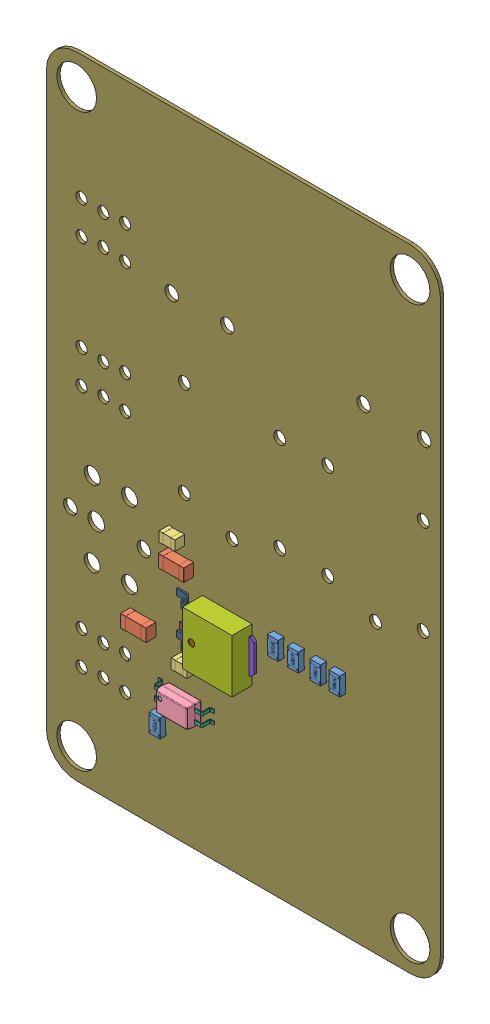
SolidWorks assembly Charge Station Board, configuration Défaut. Lengths in mm.
Overall size (49.53 79.38 2.93).
39 component instances, 12 part files, 0 mates.
Components (placement in the parent):
- Charge Station Board.step-1: Charge Station Board.step [Défaut] at origin size (49.53 79.38 2.93)
  - R5.step-1: R5.step [Défaut] at origin size (1.35 2.3 0.76)
    - res0805.step-1: res0805.step [Défaut] at (58.1659 66.4211 0) x (0 1 0) z (1 0 0) size (2.3 0.76 1.35)
  - R4.step-1: R4.step [Défaut] at origin size (1.35 2.3 0.76)
    - res0805.step-1: res0805.step [Défaut] at (60.7059 66.4211 0) x (0 1 0) z (1 0 0) size (2.3 0.76 1.35)
  - C1.step-1: C1.step [Défaut] at origin size (3.2 1.6 1.25)
    - Cap1206.step-1: Cap1206.step [Défaut] at (47.4726 70.0279 0) x (-1 0 0) z (0 1 0) size (3.2 1.25 1.6)
  - C2.step-1: C2.step [Défaut] at origin size (2 1.25 1.25)
    - Cap0805.step-1: Cap0805.step [Défaut] at (46.3551 72.5171 0) x (-1 0 0) z (0 1 0) size (2 1.25 1.25)
  - C3.step-1: C3.step [Défaut] at origin size (3.2 1.6 1.25)
    - Cap1206.step-1: Cap1206.step [Défaut] at (39.5224 59.5121 0) x (1 0 0) z (0 -1 0) size (3.2 1.25 1.6)
  - C4.step-1: C4.step [Défaut] at origin size (2 1.25 1.25)
    - Cap0805.step-1: Cap0805.step [Défaut] at (47.8791 59.4361 0) x (-1 0 0) z (0 1 0) size (2 1.25 1.25)
  - R1.step-1: R1.step [Défaut] at origin size (1.35 2.3 0.76)
    - res0805.step-1: res0805.step [Défaut] at (63.4999 66.4211 0) x (0 1 0) z (1 0 0) size (2.3 0.76 1.35)
  - R2.step-1: R2.step [Défaut] at origin size (1.35 2.3 0.76)
    - res0805.step-1: res0805.step [Défaut] at (43.3069 50.5461 0) x (0 1 0) z (1 0 0) size (2.3 0.76 1.35)
  - R3.step-1: R3.step [Défaut] at origin size (1.35 2.3 0.76)
    - res0805.step-1: res0805.step [Défaut] at (65.9129 66.4211 0) x (0 1 0) z (1 0 0) size (2.3 0.76 1.35)
  - U1.step-1: U1.step [Défaut] at origin size (7 2.51 2)
    - 916002224.step-1: 916002224.step [Défaut] at (46.609 54.483 0) x (1 0 0) z (0 0 1) size (7 2.5 2)
      - Body.step-1: Body.step [Défaut] at (-2.1 -1.25 0) size (4.2 2.5 1.8)
        - Open_CASCADE_STEP_translator_6.8_7.2.1.step-1: Open_CASCADE_STEP_translator_6.8_7.2.1.step [Défaut] at origin size (4.2 2.5 1.8)
      - Open_CASCADE_STEP_translator_6.8_7.1.step-1: Open_CASCADE_STEP_translator_6.8_7.1.step [Défaut] at (-2.1 -1.25 0.001) size (0.54 0.54 0.01)
      - Leader.step-1: Leader.step [Défaut] at (-2.1 -0.635 0) x (-1 0 0) z (0 0 1) size (1.4 0.4 1.15)
      - Leader.step-2: Leader.step [Défaut] at (-2.1 0.635 0) x (-1 0 0) z (0 0 1) size (1.4 0.4 1.15)
      - Leader.step-3: Leader.step [Défaut] at (2.1 -0.635 0) size (1.4 0.4 1.15)
      - Leader.step-4: Leader.step [Défaut] at (2.1 0.635 0) size (1.4 0.4 1.15)
  - U2.step-1: U2.step [Défaut] at origin size (9.91 6.7 2.52)
    - 916002352.step-1: 916002352.step [Défaut] at (51.698 63.627 0) x (1 0 0) z (0 0 1) size (9.91 6.7 2.52)
      - Body-1.step-1: Body-1.step [Défaut] at (-3.11 -3.35 0) size (6.22 6.7 2.52)
        - Open_CASCADE_STEP_translator_6.8_25.2.1.step-1: Open_CASCADE_STEP_translator_6.8_25.2.1.step [Défaut] at origin size (6.22 6.7 2.52)
      - tab.step-1: tab.step [Défaut] at (-3.11 -3.35 0) size (5.21 4.32 0.35)
        - Open_CASCADE_STEP_translator_6.8_25.6.1.step-1: Open_CASCADE_STEP_translator_6.8_25.6.1.step [Défaut] at origin size (5.21 4.32 0.35)
      - Open_CASCADE_STEP_translator_6.8_25.1.step-1: Open_CASCADE_STEP_translator_6.8_25.1.step [Défaut] at (-3.11 -3.35 0) size (0.85 0.85 0.01)
      - Lead.step-1: Lead.step [Défaut] at (-3.11 -2.29 0) x (-1 0 0) z (0 0 1) size (3.1 0.77 1.36)
      - Trimmed_Lead.step-1: Trimmed_Lead.step [Défaut] at (-3.11 -0.385 1.16) size (1.55 0.77 0.2)
      - Lead.step-2: Lead.step [Défaut] at (-3.11 2.29 0) x (-1 0 0) z (0 0 1) size (3.1 0.77 1.36)
  - Board.step-1: Board.step [Défaut] at (0 0 -0.4115) size (49.53 79.38 0.41)
